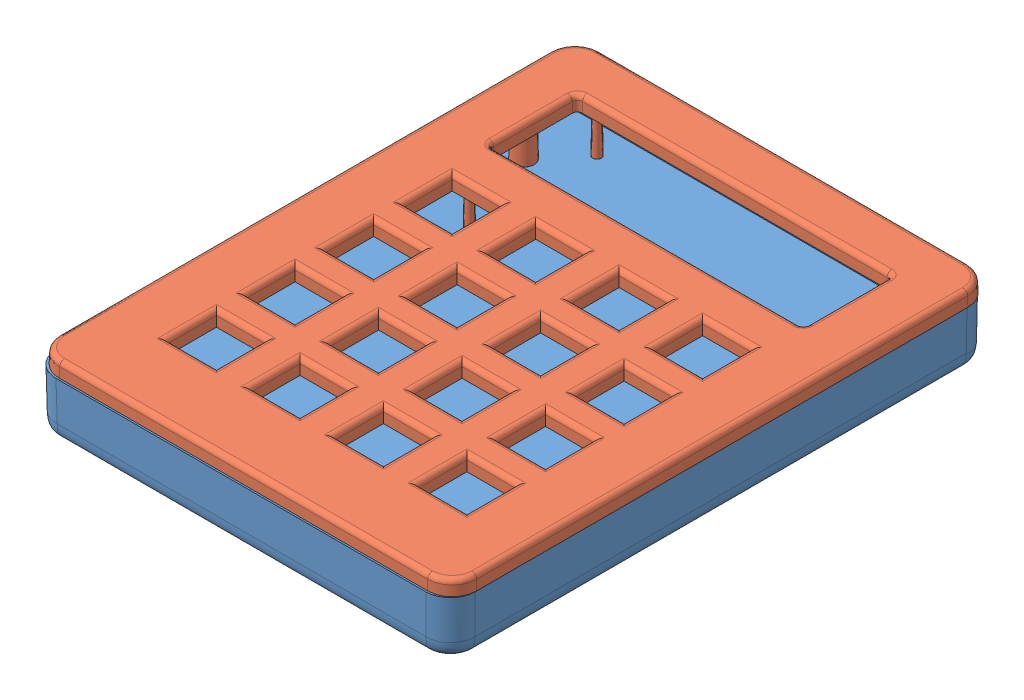
SolidWorks assembly Assem1, configuration Default. Lengths in mm.
Overall size (130.19 14.01 142.27).
2 component instances, 2 part files, 3 mates.
Components (placement in the parent):
- Part3-1: Part3 [Default] at (8.8596 28.0401 137.2443) size (130.19 11.02 142.27)
- Part4-1: Part4 [Default] at (51.5341 38.0401 82.0697) x (0 0 -1) z (1 0 0) size (110 13 85)
Mates (geometry in assembly coordinates):
- Coincident1: coincident anti-aligned: plane of Part3-1 through (8.8596 38.0401 137.2443) normal (0 1 0); plane of Part4-1 through (51.5341 38.0401 82.0697) normal (0 -1 0)
- Coincident4: coincident aligned: line of Part3-1 through (88.8603 38.0401 27.0697) axis (-1 0 0); line of Part4-1 through (89.0349 38.0401 27.0697) axis (-1 0 0)
- Coincident6: coincident aligned: line of Part3-1 through (94.0341 38.0401 132.4196) axis (0 0 -1); line of Part4-1 through (94.0341 38.0401 132.0705) axis (0 0 -1)
